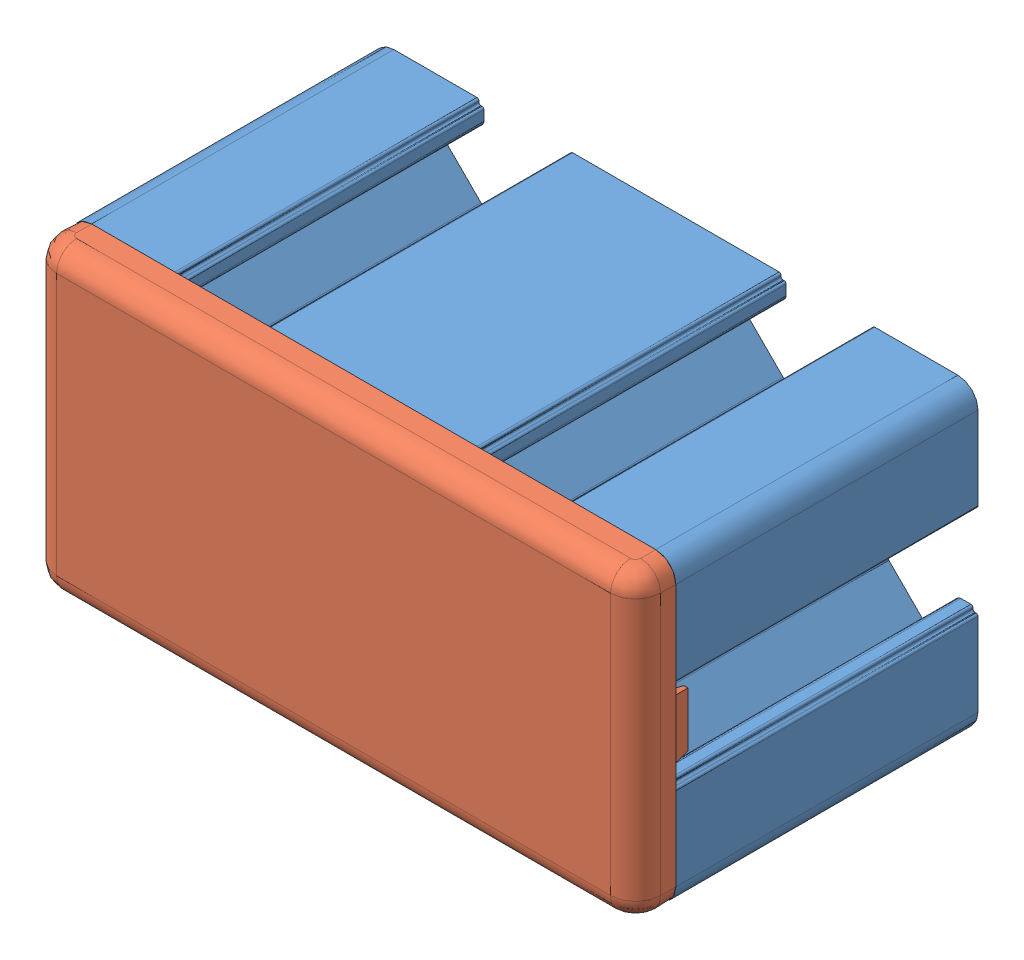
SolidWorks assembly Заглушка30х60СБ, configuration По умолчанию. Lengths in mm.
Overall size (60 30 34).
2 component instances, 2 part files, 6 mates.
Components (placement in the parent):
- 30х60 заглушка-1: 30х60 заглушка [По умолчанию] at origin size (60 30 30)
- Заглушка торцевая 30х60-1: Заглушка торцевая 30х60 [По умолчанию] at (15 0 32) x (0 0 -1) z (0 1 0) size (12 60 30)
Mates (geometry in assembly coordinates):
- Совпадение2: coincident: point of 30х60 заглушка-1
- Параллельность1: parallel anti-aligned: plane of 30х60 заглушка-1 through (0 -15 30) normal (0 -1 0)
- Совпадение4: coincident anti-aligned: plane of 30х60 заглушка-1 through (0 0 0) normal (0 0 -1)
- Совпадение5: coincident anti-aligned: plane of 30х60 заглушка-1 through (0 0 30) normal (0 0 1); plane of Заглушка торцевая 30х60-1 through (45 -15 30) normal (0 0 -1)
- Совпадение6: coincident aligned: plane of 30х60 заглушка-1 through (0 15 30) normal (0 1 0); plane of Заглушка торцевая 30х60-1 through (-12.5 15 31.5) normal (0 1 0)
- Совпадение7: coincident aligned: plane of 30х60 заглушка-1 through (45 0 30) normal (1 0 0); plane of Заглушка торцевая 30х60-1 through (45 -15 31.5) normal (1 0 0)
